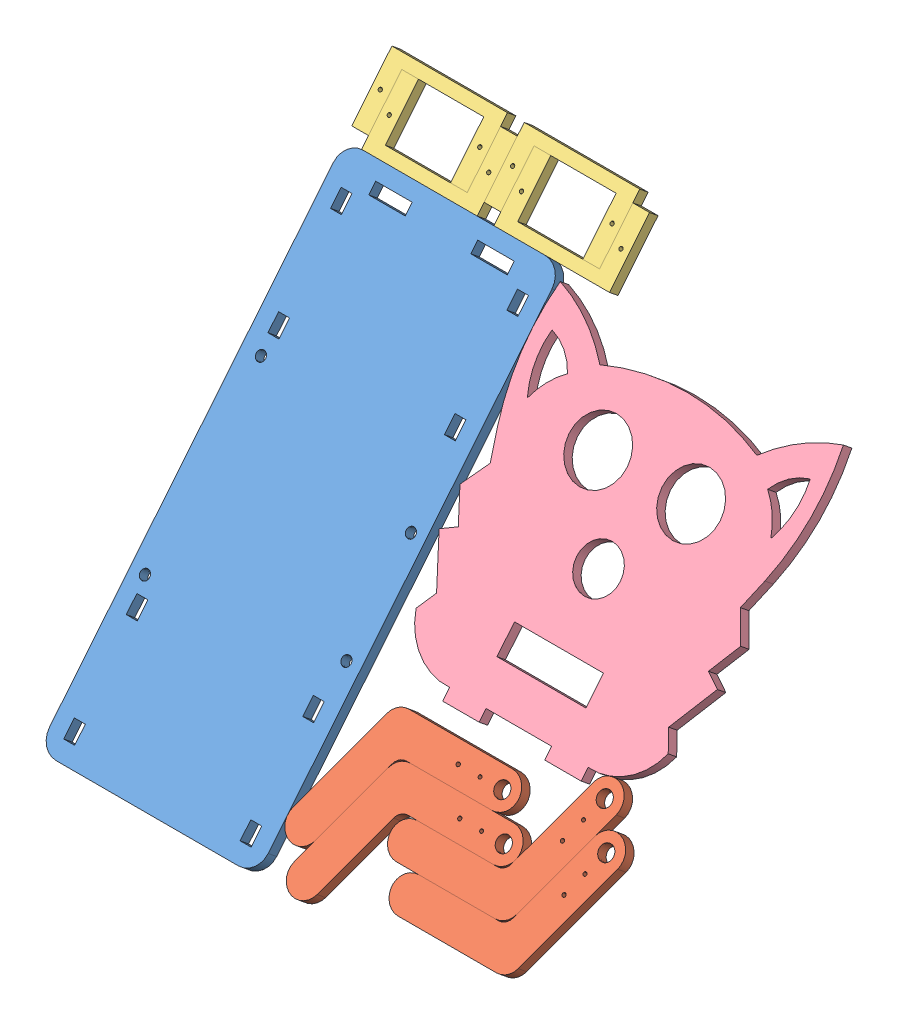
SolidWorks assembly mia_OLED_laser_cutting, configuration Default. Lengths in mm.
Overall size (150 131.69 110.02).
10 component instances, 4 part files, 30 mates.
Components (placement in the parent):
- Base-1: Base [Default] at (2.0044 259.9739 585.3012) x (1 0 0) z (0 -0.774097 0.633066) size (60 3 133)
- leg-1: leg [Default] at (79.2182 266.4842 583.8525) x (0.369302 0.719376 -0.588315) z (-0.929309 0.285876 -0.233793) size (46.53 3 35.49)
- leg-2: leg [Default] at (117.2177 253.7498 590.3913) x (1 0 0) z (0 -0.774097 0.633066) size (46.53 3 35.49)
- leg-3: leg [Default] at (85.3263 259.5173 589.5501) x (0.369302 0.719376 -0.588315) z (-0.929309 0.285876 -0.233793) size (46.53 3 35.49)
- leg-4: leg [Default] at (111.1097 260.7167 584.6937) x (1 0 0) z (0 -0.774097 0.633066) size (46.53 3 35.49)
- servo_support-5: servo_support [Default] at (38.3044 357.0457 505.9147) x (-1 0 0) z (0 0.633066 0.774097) size (31.7 17.4 3)
- servo_support-6: servo_support [Default] at (2.0044 345.8987 515.0308) x (1 0 0) z (0 0.633066 0.774097) size (31.7 17.4 3)
- servo_support-7: servo_support [Default] at (38.3044 345.8987 515.0308) x (1 0 0) z (0 0.633066 0.774097) size (31.7 17.4 3)
- servo_support-8: servo_support [Default] at (42.9044 358.9449 508.237) x (1 0 0) z (0 -0.633066 -0.774097) size (31.7 17.4 3)
- cat_face_oled-1: cat_face_oled [Default] at (60.6456 340.2973 519.6118) x (0 -0.774097 0.633066) z (0 0.633066 0.774097) size (82.31 79.65 3)
Mates (geometry in assembly coordinates):
- Coincident4: coincident: plane of leg-2 through (133.8248 271.9957 579.3451) normal (0 0.633066 0.774097); plane of leg-4 through (127.7168 278.9626 573.6475) normal (0 0.633066 0.774097)
- Coincident10: coincident: plane of leg-2 through (118.2097 254.9769 593.2633) normal (0 0.774097 -0.633066); plane of leg-4 through (90.1917 254.9769 593.2633) normal (0 -0.774097 0.633066)
- Coincident11: coincident: plane of leg-2 through (129.6429 273.2821 578.293) normal (-0.929309 0.285876 -0.233793); plane of leg-4 through (131.8987 277.6761 574.6996) normal (0.929309 -0.285876 0.233793)
- Coincident14: coincident: plane of leg-1 through (104.9755 267.0115 579.5458) normal (0 -0.774097 0.633066); plane of leg-3 through (111.0836 267.0115 579.5458) normal (0 0.774097 -0.633066)
- Coincident15: coincident: plane of leg-1 through (78.7776 265.5468 580.7436) normal (0.929309 -0.285876 0.233793); plane of leg-3 through (68.4305 245.3913 597.227) normal (-0.929309 0.285876 -0.233793)
- Coincident16: coincident: plane of leg-2 through (133.8248 270.0965 577.0228) normal (0 -0.633066 -0.774097); plane of leg-3 through (111.0836 263.528 582.3946) normal (0 -0.633066 -0.774097)
- Coincident17: coincident: plane of leg-1 through (104.9755 272.3941 579.0193) normal (0 0.633066 0.774097); plane of leg-3 through (111.0836 265.4272 584.7169) normal (0 0.633066 0.774097)
- Coincident18: coincident: plane of leg-3 through (111.0836 260.0446 585.2434) normal (0 -0.774097 0.633066); plane of leg-4 through (112.1016 261.9438 587.5657) normal (0 0.774097 -0.633066)
- Tangent1: tangent: cylinder of leg-3 through (111.0836 263.528 582.3946) axis (0 0.633066 0.774097) radius 4.5; plane of leg-4 through (123.5349 280.249 572.5954) normal (-0.929309 0.285876 -0.233793)
- Parallel1: parallel: plane of Base-1 through (7.0044 242.5206 603.4502) normal (0 -0.774097 0.633066); plane of leg-2 through (96.2997 248.01 598.9609) normal (0 -0.774097 0.633066)
- Tangent2: tangent: plane of Base-1 through (7.0044 242.5206 603.4502) normal (0 -0.774097 0.633066); cylinder of leg-3 through (72.6124 244.1049 598.2791) axis (0 0.633066 0.774097) radius 4.5
- Tangent3: tangent: plane of Base-1 through (62.0044 246.3911 600.2848) normal (1 0 0); cylinder of leg-1 through (66.5044 251.0717 592.5815) axis (0 0.633066 0.774097) radius 4.5
- Distance5: distance = 1 mm: plane of Base-1 through (2.0044 246.3911 600.2848) normal (-1 0 0); line of assembly
- Distance6: distance = 1 mm: plane of Base-1 through (7.0044 242.5206 603.4502) normal (0 -0.774097 0.633066); line of assembly
- Coincident35: coincident: plane of Base-1 through (57.0044 246.3911 600.2848) normal (0 0.633066 0.774097); plane of servo_support-5 through (38.3044 358.9449 508.237) normal (0 0.633066 0.774097)
- Coincident37: coincident: plane of servo_support-5 through (38.3044 358.9449 508.237) normal (0 0.633066 0.774097); plane of servo_support-6 through (2.0044 347.7979 517.3531) normal (0 0.633066 0.774097)
- Coincident38: coincident: plane of servo_support-5 through (33.7044 358.9449 508.237) normal (-1 0 0); plane of servo_support-6 through (33.7044 347.7979 517.3531) normal (1 0 0)
- Coincident39: coincident: plane of servo_support-5 through (33.7044 347.7979 517.3531) normal (0 0.774097 -0.633066); plane of servo_support-6 through (29.1044 347.7979 517.3531) normal (0 -0.774097 0.633066)
- Coincident40: coincident: plane of Base-1 through (7.0044 345.4756 519.2523) normal (0 0.774097 -0.633066); plane of servo_support-5 through (6.6044 345.4756 519.2523) normal (0 -0.774097 0.633066)
- Coincident41: coincident: plane of Base-1 through (2.0044 246.3911 600.2848) normal (-1 0 0); plane of servo_support-6 through (2.0044 361.2672 506.3378) normal (-1 0 0)
- Coincident42: coincident: plane of servo_support-5 through (38.3044 345.4756 519.2523) normal (1 0 0); plane of servo_support-7 through (38.3044 361.2672 506.3378) normal (-1 0 0)
- Coincident43: coincident: plane of Base-1 through (57.0044 246.3911 600.2848) normal (0 0.633066 0.774097); plane of servo_support-7 through (38.3044 347.7979 517.3531) normal (0 0.633066 0.774097)
- Coincident44: coincident: plane of servo_support-6 through (33.7044 361.2672 506.3378) normal (0 0.774097 -0.633066); plane of servo_support-7 through (70.0044 361.2672 506.3378) normal (0 0.774097 -0.633066)
- Coincident45: coincident: plane of Base-1 through (57.0044 246.3911 600.2848) normal (0 0.633066 0.774097); plane of servo_support-8 through (42.9044 358.9449 508.237) normal (0 0.633066 0.774097)
- Coincident47: coincident: plane of Base-1 through (7.0044 345.4756 519.2523) normal (0 0.774097 -0.633066); plane of servo_support-8 through (74.6044 343.5764 516.93) normal (0 -0.774097 0.633066)
- Coincident48: coincident: plane of servo_support-7 through (42.9044 347.7979 517.3531) normal (1 0 0); plane of servo_support-8 through (42.9044 343.5764 516.93) normal (-1 0 0)
- Coincident49: coincident: plane of Base-1 through (57.0044 246.3911 600.2848) normal (0 0.633066 0.774097); plane of cat_face_oled-1 through (79.179 337.2052 526.016) normal (0 0.633066 0.774097)
- Parallel2: parallel: plane of Base-1 through (7.0044 242.5206 603.4502) normal (0 -0.774097 0.633066); plane of cat_face_oled-1 through (82.8269 279.4697 573.2328) normal (0 -0.774097 0.633066)
- Tangent4: tangent: plane of Base-1 through (62.0044 246.3911 600.2848) normal (1 0 0); cylinder of cat_face_oled-1 through (124.4748 334.6258 528.1254) axis (0 -0.633066 -0.774097) radius 62.4704
- Tangent5: tangent: cylinder of leg-4 through (127.7168 278.9626 573.6475) axis (0 -0.633066 -0.774097) radius 4.5; cylinder of cat_face_oled-1 through (121.8486 293.7947 561.5176) axis (0 -0.633066 -0.774097) radius 15.5391
